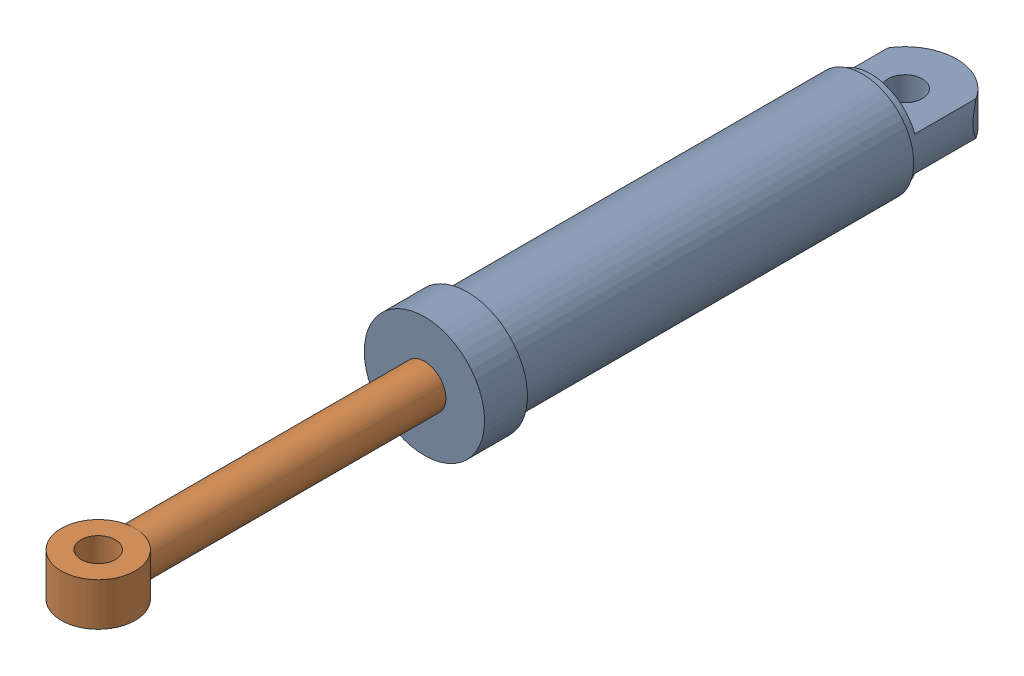
SolidWorks assembly SylinderB, configuration Default. Lengths in mm.
Overall size (140 140 1043).
2 component instances, 2 part files, 3 mates.
Components (placement in the parent):
- SylHusingB-1: SylHusingB [Default] at origin size (140 140 620)
- SylStempelB-1: SylStempelB [Default] at (0 0 305) size (90 90 603)
Mates (geometry in assembly coordinates):
- Coincident2: coordinate: point of SylHusingA-1
- Concentric1: concentric aligned: cylinder of SylHusingA-1 through (0 0 0) axis (0 0 -1) radius 45; cylinder of SylStempelA-1 through (0 0 380) axis (0 0 -1) radius 45
- LimitDistance1: limit distance = 0 mm anti-aligned: plane of SylStempelB-1 through (45 0 480) normal (0 0 1); plane of SylHusingB-1 through (25 0 480) normal (0 0 -1)
